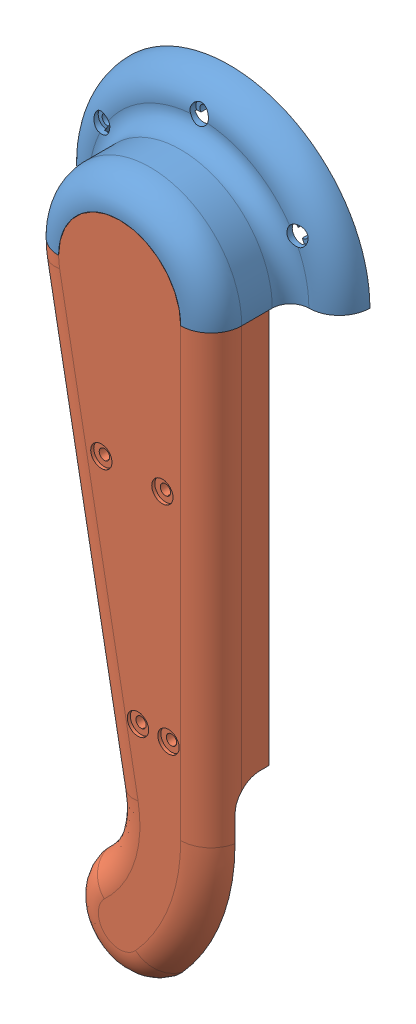
SolidWorks assembly 上盖加工, configuration 默认. Lengths in mm.
Overall size (92 242.8 36.56).
2 component instances, 2 part files, 2 mates.
Components (placement in the parent):
- 外壳上盖1-1: 外壳上盖1 [默认] at (-7.8521 -15.9994 72) size (92 46 36)
- 外壳上盖2-1: 外壳上盖2 [默认] at (-7.8521 -15.9994 72) size (60 216.8 19.56)
Mates (geometry in assembly coordinates):
- 重合1: coincident anti-aligned: plane of 外壳上盖1-1 through (-7.8521 -15.9994 72) normal (0 -1 0); plane of 外壳上盖2-1 through (-7.8521 -15.9994 72) normal (0 1 0)
- 重合2: coincident aligned: circle of 外壳上盖1-1; circle of 外壳上盖2-1
